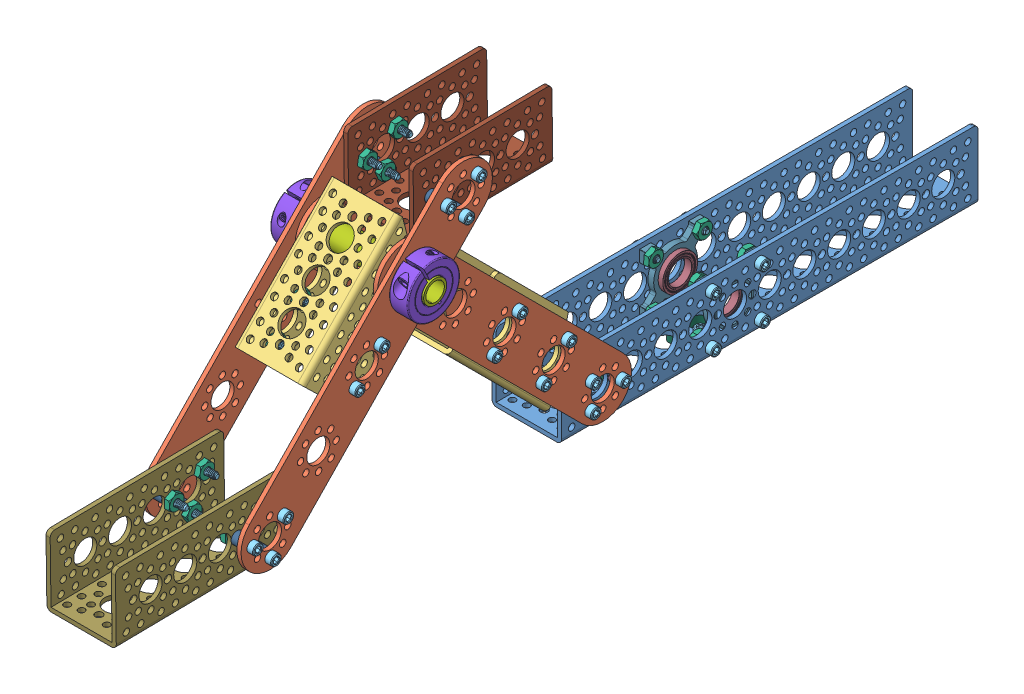
SolidWorks assembly Rocker-Bogie Assembly, configuration Default. Lengths in mm.
Overall size (76.23 183.82 473.44).
136 component instances, 15 part files, 99 mates.
Components (placement in the parent):
- 9 Aluminum Channel-1: 9 Aluminum Channel [Default] at (-19.05 0 0) size (38.1 38.1 228.6)
- Pattern F Bracket-1: Pattern F Bracket [Default] at (-20.32 72.9315 263.4315) x (0 0.707107 0.707107) z (0 -0.707107 0.707107) size (184.15 2.29 31.75)
- 3 Aluminum Channel Mod-1: 3 Aluminum Channel Mod [Default] at (-19.05 19.05 236.4908) x (1 0 0) z (0 0.707107 0.707107) size (38.1 38.1 76.2)
- 6-32 Washer-3: 6-32 Washer [Default] at (-20.32 12.1352 216.4648) x (0 0 -1) z (1 0 0) size (6.35 6.35 1.27)
- 6-32 Washer-6: 6-32 Washer [Default] at (-20.32 66.0167 270.3463) x (0 0 -1) z (1 0 0) size (6.35 6.35 1.27)
- 6-32 Washer-7: 6-32 Washer [Default] at (-20.32 79.8463 256.5167) x (0 0 -1) z (1 0 0) size (6.35 6.35 1.27)
- 6-32 Washer-8: 6-32 Washer [Default] at (-20.32 52.9056 229.576) x (0 -0.924225 -0.381849) z (1 0 0) size (6.35 6.35 1.27)
- 6-32 Washer-9: 6-32 Washer [Default] at (-20.32 39.076 243.4056) x (0 0 -1) z (1 0 0) size (6.35 6.35 1.27)
- 6-32_SHCS-2: 6-32_SHCS [6-32 SHCS X .375] at (-13.081 66.0167 270.3463) x (0 0.924225 0.381849) z (-1 0 0) size (5.74 5.74 13.03)
- 6-32_SHCS-6: 6-32_SHCS [6-32 SHCS X .375] at (-13.081 79.8463 256.5167) x (0 0.924225 0.381849) z (-1 0 0) size (5.74 5.74 13.03)
- 6-32_SHCS-7: 6-32_SHCS [6-32 SHCS X .375] at (-13.081 52.9056 229.576) x (0 0.924225 0.381849) z (-1 0 0) size (5.74 5.74 13.03)
- 6-32_SHCS-8: 6-32_SHCS [6-32 SHCS X .375] at (-13.081 12.1352 216.4648) x (0 0.924225 0.381849) z (-1 0 0) size (5.74 5.74 13.03)
- 6-32_SHCS-9: 6-32_SHCS [6-32 SHCS X .375] at (-13.081 39.076 243.4056) x (0 0 1) z (-1 0 0) size (5.74 5.74 13.03)
- hex_nut-1: hex_nut [#6-32] at (-16.764 79.8463 256.5167) x (0 0.381849 -0.924225) z (0 -0.924225 -0.381849) size (7.92 2.9 10.06)
- hex_nut-2: hex_nut [#6-32] at (-16.764 39.076 243.4056) x (0 0.381849 -0.924225) z (0 -0.924225 -0.381849) size (7.92 2.9 10.06)
- hex_nut-3: hex_nut [#6-32] at (-16.764 12.1352 216.4648) x (0 0.381849 -0.924225) z (0 -0.924225 -0.381849) size (7.92 2.9 10.06)
- hex_nut-4: hex_nut [#6-32] at (-16.764 52.9056 229.576) x (0 -0.870942 -0.491386) z (0 -0.491386 0.870942) size (7.92 2.9 10.06)
- hex_nut-5: hex_nut [#6-32] at (-16.764 66.0167 270.3463) x (0 0.381849 -0.924225) z (0 -0.924225 -0.381849) size (7.92 2.9 10.06)
- hex_nut-10: hex_nut [#6-32] at (-16.764 18.8793 199.7725) x (0 0.399577 0.9167) z (0 0.9167 -0.399577) size (7.92 2.9 10.06)
- hex_nut-11: hex_nut [#6-32] at (-16.764 26.2019 216.2193) x (0 -0.936988 -0.349362) z (0 -0.349362 0.936988) size (7.92 2.9 10.06)
- 6-32 Washer-10: 6-32 Washer [Default] at (-20.32 18.8793 199.7725) x (0 0.71934 0.694658) z (1 0 0) size (6.35 6.35 1.27)
- 6-32 Washer-11: 6-32 Washer [Default] at (-20.32 26.2019 216.2193) x (0 -0.999391 0.034899) z (1 0 0) size (6.35 6.35 1.27)
- 6-32_SHCS-10: 6-32_SHCS [6-32 SHCS X .375] at (-13.081 18.8793 199.7725) x (0 -0.9167 0.399577) z (-1 0 0) size (5.74 5.74 13.03)
- 6-32_SHCS-11: 6-32_SHCS [6-32 SHCS X .375] at (-13.081 26.2019 216.2193) x (0 0.349362 -0.936988) z (-1 0 0) size (5.74 5.74 13.03)
- 3inch Aluminum Rod-1: 3inch Aluminum Rod [Default] at (-37.7507 126.8131 317.3131) x (1 0 0) z (0 0.999969 -0.00781) size (76.2 12.7 12.7)
- .5in Collared Clamp-1: .5in Collared Clamp [6157K14] at (-32.5914 126.8131 317.3131) x (0 -0.43021 0.902729) z (-1 0 0) size (28.57 28.59 10.38)
- 0.5 Nylon Plastic Washer-1: 0.5 Nylon Plastic Washer [Default] at (-25.146 126.8131 317.3131) x (0 0 -1) z (1 0 0) size (19.05 19.05 1.27)
- 0.5 Nylon Plastic Washer-2: 0.5 Nylon Plastic Washer [Default] at (-19.05 126.8131 317.3131) x (0 0 1) z (-1 0 0) size (19.05 19.05 1.27)
- 0.5 Nylon Plastic Washer-3: 0.5 Nylon Plastic Washer [Default] at (-22.606 126.8131 317.3131) x (0 0 1) z (-1 0 0) size (19.05 19.05 1.27)
- Pattern F Bracket-2: Pattern F Bracket [Default] at (-27.432 99.4919 343.868) x (0 -0.717092 0.696979) z (0 0.696979 0.717092) size (184.15 2.29 31.75)
- 3 Aluminum Channel Mod-2: 3 Aluminum Channel Mod [Default] at (19.05 153.7511 317.6962) x (-1 0 0) z (0 -0.717092 0.696979) size (38.1 38.1 76.2)
- 6-32_L0_25 Spacer-1: 6-32_L0_25 Spacer [Default] at (-25.4 92.4794 350.6837) size (6.35 6.35 6.35)
- 6-32_L0_25 Spacer-2: 6-32_L0_25 Spacer [Default] at (-25.4 144.3563 290.6191) size (6.35 6.35 6.35)
- 6-32_L0_25 Spacer-4: 6-32_L0_25 Spacer [Default] at (-25.4 35.0715 396.8387) size (6.35 6.35 6.35)
- 6-32_L0_25 Spacer-5: 6-32_L0_25 Spacer [Default] at (-25.4 106.5043 337.0522) size (6.35 6.35 6.35)
- 3 Aluminum Channel-1: 3 Aluminum Channel [Default] at (-19.05 135.899 233.343) x (1 0 0) z (0 -0.014222 0.999899) size (38.1 38.1 76.2)
- 6-32_SHCS-12: 6-32_SHCS [6-32 SHCS X .750] at (-8.382 92.4794 350.6837) x (0 0.924225 0.381849) z (-1 0 0) size (5.74 5.74 22.56)
- 6-32_SHCS-13: 6-32_SHCS [6-32 SHCS X .750] at (-8.382 144.3563 290.6191) x (0 0.924225 0.381849) z (-1 0 0) size (5.74 5.74 22.56)
- 6-32_SHCS-15: 6-32_SHCS [6-32 SHCS X .750] at (-8.382 106.5043 337.0522) x (0 0.924225 0.381849) z (-1 0 0) size (5.74 5.74 22.56)
- 6-32_SHCS-16: 6-32_SHCS [6-32 SHCS X .750] at (-8.382 35.0715 396.8387) x (0 0 1) z (-1 0 0) size (5.74 5.74 22.56)
- 3.75 Aluminum Channel-1: 3.75 Aluminum Channel [Default] at (-19.05 26.0724 377.6588) x (1 0 0) z (0 -0.014222 0.999899) size (38.1 38.1 95.25)
- hex_nut-12: hex_nut [#6-32] at (-16.764 144.3563 290.6191) x (0 0.381849 -0.924225) z (0 -0.924225 -0.381849) size (7.92 2.9 10.06)
- hex_nut-14: hex_nut [#6-32] at (-16.764 106.5043 337.0522) x (0 0.425863 -0.904788) z (0 -0.904788 -0.425863) size (7.92 2.9 10.06)
- hex_nut-15: hex_nut [#6-32] at (-16.764 92.4794 350.6837) x (0 0.425863 -0.904788) z (0 -0.904788 -0.425863) size (7.92 2.9 10.06)
- hex_nut-16: hex_nut [#6-32] at (-16.764 35.0715 396.8387) x (0 -1 0) z (0 0 1) size (7.92 2.9 10.06)
- hex_nut-17: hex_nut [#6-32] at (-16.764 161.0267 283.8211) x (0 0.399577 0.9167) z (0 0.9167 -0.399577) size (7.92 2.9 10.06)
- hex_nut-18: hex_nut [#6-32] at (-16.764 154.3365 300.5351) x (0 -0.936988 -0.349362) z (0 -0.349362 0.936988) size (7.92 2.9 10.06)
- 6-32_L0_25 Spacer-6: 6-32_L0_25 Spacer [Default] at (-25.4 161.0267 283.8211) x (1 0 0) z (0 -0.71934 -0.694658) size (6.35 6.35 6.35)
- 6-32_L0_25 Spacer-7: 6-32_L0_25 Spacer [Default] at (-25.4 154.3365 300.5351) x (1 0 0) z (0 0.999391 -0.034899) size (6.35 6.35 6.35)
- 6-32_SHCS-17: 6-32_SHCS [6-32 SHCS X .750] at (-8.382 161.0267 283.8211) x (0 -0.9167 0.399577) z (-1 0 0) size (5.74 5.74 22.56)
- 6-32_SHCS-18: 6-32_SHCS [6-32 SHCS X .750] at (-8.382 154.3365 300.5351) x (0 0.349362 -0.936988) z (-1 0 0) size (5.74 5.74 22.56)
- hex_nut-19: hex_nut [#6-32] at (-16.764 51.7419 390.0407) x (0 0.694658 -0.71934) z (0 -0.71934 -0.694658) size (7.92 2.9 10.06)
- hex_nut-20: hex_nut [#6-32] at (-16.764 45.0518 406.7547) x (0 0.034899 0.999391) z (0 0.999391 -0.034899) size (7.92 2.9 10.06)
- 6-32_L0_25 Spacer-8: 6-32_L0_25 Spacer [Default] at (-25.4 51.7419 390.0407) x (1 0 0) z (0 -0.71934 -0.694658) size (6.35 6.35 6.35)
- 6-32_L0_25 Spacer-9: 6-32_L0_25 Spacer [Default] at (-25.4 45.0518 406.7547) x (1 0 0) z (0 0.999391 -0.034899) size (6.35 6.35 6.35)
- 6-32_SHCS-19: 6-32_SHCS [6-32 SHCS X .750] at (-8.382 51.7419 390.0407) x (0 -0.71934 -0.694658) z (-1 0 0) size (5.74 5.74 22.56)
- 6-32_SHCS-20: 6-32_SHCS [6-32 SHCS X .750] at (-8.382 45.0518 406.7547) x (0 0.999391 -0.034899) z (-1 0 0) size (5.74 5.74 22.56)
- 6-32_L0_25 Spacer-10: 6-32_L0_25 Spacer [Default] at (25.4 45.0518 406.7547) x (-1 0 0) z (0 -0.999391 0.034899) size (6.35 6.35 6.35)
- 6-32_SHCS-21: 6-32_SHCS [6-32 SHCS X .750] at (8.382 45.0518 406.7547) x (0 -0.999391 0.034899) z (1 0 0) size (5.74 5.74 22.56)
- 6-32_SHCS-22: 6-32_SHCS [6-32 SHCS X .750] at (8.382 35.0715 396.8387) x (0 0 -1) z (1 0 0) size (5.74 5.74 22.56)
- 6-32_L0_25 Spacer-11: 6-32_L0_25 Spacer [Default] at (25.4 35.0715 396.8387) x (-1 0 0) z (0 0 -1) size (6.35 6.35 6.35)
- 6-32_L0_25 Spacer-12: 6-32_L0_25 Spacer [Default] at (25.4 51.7419 390.0407) x (-1 0 0) z (0 0.71934 0.694658) size (6.35 6.35 6.35)
- 6-32_SHCS-23: 6-32_SHCS [6-32 SHCS X .750] at (8.382 51.7419 390.0407) x (0 0.71934 0.694658) z (1 0 0) size (5.74 5.74 22.56)
- Pattern F Bracket-3: Pattern F Bracket [Default] at (27.432 99.4919 343.868) x (0 0.717092 -0.696979) z (0 0.696979 0.717092) size (184.15 2.29 31.75)
- hex_nut-21: hex_nut [#6-32] at (16.764 35.0715 396.8387) x (0 -1 0) z (0 0 -1) size (7.92 2.9 10.06)
- hex_nut-22: hex_nut [#6-32] at (16.764 45.0518 406.7547) x (0 0.034899 0.999391) z (0 -0.999391 0.034899) size (7.92 2.9 10.06)
- hex_nut-23: hex_nut [#6-32] at (16.764 51.7419 390.0407) x (0 0.694658 -0.71934) z (0 0.71934 0.694658) size (7.92 2.9 10.06)
- hex_nut-24: hex_nut [#6-32] at (16.764 92.4794 350.6837) x (0 0.425863 -0.904788) z (0 0.904788 0.425863) size (7.92 2.9 10.06)
- 6-32_SHCS-24: 6-32_SHCS [6-32 SHCS X .750] at (8.382 92.4794 350.6837) x (0 -0.924225 -0.381849) z (1 0 0) size (5.74 5.74 22.56)
- 6-32_SHCS-25: 6-32_SHCS [6-32 SHCS X .750] at (8.382 106.5043 337.0522) x (0 -0.924225 -0.381849) z (1 0 0) size (5.74 5.74 22.56)
- hex_nut-25: hex_nut [#6-32] at (16.764 106.5043 337.0522) x (0 0.425863 -0.904788) z (0 0.904788 0.425863) size (7.92 2.9 10.06)
- .5in Collared Clamp-2: .5in Collared Clamp [6157K14] at (32.5914 126.8131 317.3131) x (0 0.43021 -0.902729) z (1 0 0) size (28.57 28.59 10.38)
- 0.5 Nylon Plastic Washer-4: 0.5 Nylon Plastic Washer [Default] at (23.876 126.8131 317.3131) x (0 0 -1) z (1 0 0) size (19.05 19.05 1.27)
- 0.5 Nylon Plastic Washer-5: 0.5 Nylon Plastic Washer [Default] at (23.876 126.8131 317.3131) x (0 0 1) z (-1 0 0) size (19.05 19.05 1.27)
- 0.5 Nylon Plastic Washer-6: 0.5 Nylon Plastic Washer [Default] at (20.32 126.8131 317.3131) x (0 0 1) z (-1 0 0) size (19.05 19.05 1.27)
- 6-32_L0_25 Spacer-13: 6-32_L0_25 Spacer [Default] at (25.4 92.4794 350.6837) x (-1 0 0) z (0 0 -1) size (6.35 6.35 6.35)
- 6-32_L0_25 Spacer-14: 6-32_L0_25 Spacer [Default] at (25.4 106.5043 337.0522) x (-1 0 0) z (0 0 -1) size (6.35 6.35 6.35)
- 6-32_L0_25 Spacer-15: 6-32_L0_25 Spacer [Default] at (25.4 154.3365 300.5351) x (-1 0 0) z (0 -0.999391 0.034899) size (6.35 6.35 6.35)
- 6-32_L0_25 Spacer-16: 6-32_L0_25 Spacer [Default] at (25.4 161.0267 283.8211) x (-1 0 0) z (0 0.71934 0.694658) size (6.35 6.35 6.35)
- 6-32_L0_25 Spacer-17: 6-32_L0_25 Spacer [Default] at (25.4 144.3563 290.6191) x (-1 0 0) z (0 0 -1) size (6.35 6.35 6.35)
- 6-32_SHCS-26: 6-32_SHCS [6-32 SHCS X .750] at (8.382 144.3563 290.6191) x (0 -0.924225 -0.381849) z (1 0 0) size (5.74 5.74 22.56)
- 6-32_SHCS-27: 6-32_SHCS [6-32 SHCS X .750] at (8.382 154.3365 300.5351) x (0 -0.349362 0.936988) z (1 0 0) size (5.74 5.74 22.56)
- 6-32_SHCS-28: 6-32_SHCS [6-32 SHCS X .750] at (8.382 161.0267 283.8211) x (0 0.9167 -0.399577) z (1 0 0) size (5.74 5.74 22.56)
- 6-32_SHCS-29: 6-32_SHCS [6-32 SHCS X .375] at (13.081 79.8463 256.5167) x (0 -0.924225 -0.381849) z (1 0 0) size (5.74 5.74 13.03)
- 6-32_SHCS-30: 6-32_SHCS [6-32 SHCS X .375] at (13.081 52.9056 229.576) x (0 -0.924225 -0.381849) z (1 0 0) size (5.74 5.74 13.03)
- 6-32_SHCS-31: 6-32_SHCS [6-32 SHCS X .375] at (13.081 18.8793 199.7725) x (0 0.9167 -0.399577) z (1 0 0) size (5.74 5.74 13.03)
- 6-32_SHCS-32: 6-32_SHCS [6-32 SHCS X .375] at (13.081 26.2019 216.2193) x (0 -0.349362 0.936988) z (1 0 0) size (5.74 5.74 13.03)
- 6-32_SHCS-33: 6-32_SHCS [6-32 SHCS X .375] at (13.081 39.076 243.4056) x (0 0 -1) z (1 0 0) size (5.74 5.74 13.03)
- 6-32_SHCS-34: 6-32_SHCS [6-32 SHCS X .375] at (13.081 66.0167 270.3463) x (0 -0.924225 -0.381849) z (1 0 0) size (5.74 5.74 13.03)
- 6-32_SHCS-35: 6-32_SHCS [6-32 SHCS X .375] at (13.081 12.1352 216.4648) x (0 -0.924225 -0.381849) z (1 0 0) size (5.74 5.74 13.03)
- 6-32 Washer-12: 6-32 Washer [Default] at (19.05 18.8793 199.7725) x (0 0.71934 0.694658) z (1 0 0) size (6.35 6.35 1.27)
- 6-32 Washer-13: 6-32 Washer [Default] at (19.05 12.1352 216.4648) x (0 0 -1) z (1 0 0) size (6.35 6.35 1.27)
- 6-32 Washer-14: 6-32 Washer [Default] at (19.05 26.2019 216.2193) x (0 -0.999391 0.034899) z (1 0 0) size (6.35 6.35 1.27)
- 6-32 Washer-15: 6-32 Washer [Default] at (19.05 39.076 243.4056) x (0 0 -1) z (1 0 0) size (6.35 6.35 1.27)
- 6-32 Washer-16: 6-32 Washer [Default] at (19.05 52.9056 229.576) x (0 -0.924225 -0.381849) z (1 0 0) size (6.35 6.35 1.27)
- 6-32 Washer-17: 6-32 Washer [Default] at (19.05 79.8463 256.5167) x (0 0 -1) z (1 0 0) size (6.35 6.35 1.27)
- 6-32 Washer-18: 6-32 Washer [Default] at (19.05 66.0167 270.3463) x (0 0 -1) z (1 0 0) size (6.35 6.35 1.27)
- Pattern F Bracket-4: Pattern F Bracket [Default] at (22.606 72.9315 263.4315) x (0 -0.707107 -0.707107) z (0 0.707107 -0.707107) size (184.15 2.29 31.75)
- 0.5 Pillow Bearing Block-1: 0.5 Pillow Bearing Block [Default] at (-23.869 27.3261 118.2131) x (0 -0.904025 -0.427479) z (0 -0.427479 0.904025) size (44.3 7.64 44.3)
  - 0.5 Bearing-1: 0.5 Bearing [Default] at (1.0111 10.8528 17.222) size (19.05 3.97 19.05)
  - 0.5 Bearing Block-1: 0.5 Bearing Block [Default] at (1.0111 10.28 17.222) x (-0.904025 0 -0.427479) z (-0.427479 0 0.904025) size (33.27 5.08 33.27)
- 0.5 Pillow Bearing Block-2: 0.5 Pillow Bearing Block [Default] at (23.869 3.9131 141.6261) x (0 -0.427479 -0.904025) z (0 0.904025 -0.427479) size (44.3 7.64 44.3)
  - 0.5 Bearing-1: 0.5 Bearing [Default] at (1.0111 10.8528 17.222) size (19.05 3.97 19.05)
  - 0.5 Bearing Block-1: 0.5 Bearing Block [Default] at (1.0111 10.28 17.222) x (-0.904025 0 -0.427479) z (-0.427479 0 0.904025) size (33.27 5.08 33.27)
- 6-32_SHCS-36: 6-32_SHCS [6-32 SHCS X .375] at (-9.525 32.5204 119.8796) x (0 0.00007 1) z (-1 0 0) size (5.74 5.74 13.03)
- hex_nut-26: hex_nut [#6-32] at (-13.589 32.5204 119.8796) x (0 0.442098 -0.896967) z (0 -0.896967 -0.442098) size (7.92 2.9 10.06)
- 6-32_SHCS-37: 6-32_SHCS [6-32 SHCS X .375] at (-9.525 5.5796 119.8796) x (0 1 -0.00007) z (-1 0 0) size (5.74 5.74 13.03)
- 6-32_SHCS-38: 6-32_SHCS [6-32 SHCS X .375] at (-9.525 5.5796 146.8204) x (0 -0.00007 -1) z (-1 0 0) size (5.74 5.74 13.03)
- 6-32_SHCS-39: 6-32_SHCS [6-32 SHCS X .375] at (-9.525 32.5204 146.8204) x (0 -1 0.00007) z (-1 0 0) size (5.74 5.74 13.03)
- hex_nut-27: hex_nut [#6-32] at (-13.589 5.5796 119.8796) x (0 -0.896967 -0.442098) z (0 -0.442098 0.896967) size (7.92 2.9 10.06)
- hex_nut-28: hex_nut [#6-32] at (-13.589 5.5796 146.8204) x (0 -0.442098 0.896967) z (0 0.896967 0.442098) size (7.92 2.9 10.06)
- hex_nut-29: hex_nut [#6-32] at (-13.589 32.5204 146.8204) x (0 0.896967 0.442098) z (0 0.442098 -0.896967) size (7.92 2.9 10.06)
- 6-32_SHCS-40: 6-32_SHCS [6-32 SHCS X .375] at (9.525 32.5204 119.8796) x (0 -0.00007 -1) z (1 0 0) size (5.74 5.74 13.03)
- hex_nut-30: hex_nut [#6-32] at (13.589 32.5204 119.8796) x (0 0.442098 -0.896967) z (0 0.896967 0.442098) size (7.92 2.9 10.06)
- 6-32_SHCS-41: 6-32_SHCS [6-32 SHCS X .375] at (9.525 5.5796 119.8796) x (0 -1 0.00007) z (1 0 0) size (5.74 5.74 13.03)
- 6-32_SHCS-42: 6-32_SHCS [6-32 SHCS X .375] at (9.525 5.5796 146.8204) x (0 0.00007 1) z (1 0 0) size (5.74 5.74 13.03)
- 6-32_SHCS-43: 6-32_SHCS [6-32 SHCS X .375] at (9.525 32.5204 146.8204) x (0 1 -0.00007) z (1 0 0) size (5.74 5.74 13.03)
- hex_nut-31: hex_nut [#6-32] at (13.589 5.5796 119.8796) x (0 -0.896967 -0.442098) z (0 0.442098 -0.896967) size (7.92 2.9 10.06)
- hex_nut-32: hex_nut [#6-32] at (13.589 5.5796 146.8204) x (0 -0.442098 0.896967) z (0 -0.896967 -0.442098) size (7.92 2.9 10.06)
- hex_nut-33: hex_nut [#6-32] at (13.589 32.5204 146.8204) x (0 0.896967 0.442098) z (0 -0.442098 0.896967) size (7.92 2.9 10.06)
- 0.5 Bore Side Tapped Clamping Hub-1: 0.5 Bore Side Tapped Clamping Hub [Default] at (33.5255 -18.6705 120.2928) size (20.57 7.21 26.29)
  - 545600-1: 545600 [Default] at (-33.5255 9.1455 13.0572) size (20.57 7.21 26.29)
- 6-32_SHCS-44: 6-32_SHCS [6-32 SHCS X .375] at (-6.9148 -7.239 140.2648) x (1 0 0) z (0 1 0) size (5.74 5.74 13.03)
- 6-32_SHCS-45: 6-32_SHCS [6-32 SHCS X .375] at (-6.9148 -7.239 126.4352) x (0 0 1) z (0 1 0) size (5.74 5.74 13.03)
- 6-32_SHCS-46: 6-32_SHCS [6-32 SHCS X .375] at (6.9148 -7.239 126.4352) x (-1 0 0) z (0 1 0) size (5.74 5.74 13.03)
- 6-32_SHCS-47: 6-32_SHCS [6-32 SHCS X .375] at (6.9148 -7.239 140.2648) x (0 0 -1) z (0 1 0) size (5.74 5.74 13.03)
- hex_nut-34: hex_nut [#6-32] at (16.764 52.9056 229.576) x (0 -0.870942 -0.491386) z (0 0.491386 -0.870942) size (7.92 2.9 10.06)
- hex_nut-35: hex_nut [#6-32] at (16.764 39.076 243.4056) x (0 0.381849 -0.924225) z (0 0.924225 0.381849) size (7.92 2.9 10.06)
- hex_nut-36: hex_nut [#6-32] at (16.764 26.2019 216.2193) x (0 -0.936988 -0.349362) z (0 0.349362 -0.936988) size (7.92 2.9 10.06)
- hex_nut-37: hex_nut [#6-32] at (16.764 12.1352 216.4648) x (0 0.381849 -0.924225) z (0 0.924225 0.381849) size (7.92 2.9 10.06)
- hex_nut-38: hex_nut [#6-32] at (16.764 18.8793 199.7725) x (0 0.399577 0.9167) z (0 -0.9167 0.399577) size (7.92 2.9 10.06)
- hex_nut-39: hex_nut [#6-32] at (16.764 79.8463 256.5167) x (0 0.381849 -0.924225) z (0 0.924225 0.381849) size (7.92 2.9 10.06)
- hex_nut-40: hex_nut [#6-32] at (16.764 66.0167 270.3463) x (0 0.381849 -0.924225) z (0 0.924225 0.381849) size (7.92 2.9 10.06)
- hex_nut-41: hex_nut [#6-32] at (16.764 154.3365 300.5351) x (0 -0.936988 -0.349362) z (0 0.349362 -0.936988) size (7.92 2.9 10.06)
- hex_nut-42: hex_nut [#6-32] at (16.764 161.0267 283.8211) x (0 0.399577 0.9167) z (0 -0.9167 0.399577) size (7.92 2.9 10.06)
- hex_nut-43: hex_nut [#6-32] at (16.764 144.3563 290.6191) x (0 0.381849 -0.924225) z (0 0.924225 0.381849) size (7.92 2.9 10.06)
Mates (geometry in assembly coordinates):
- Concentric1: concentric aligned: cylinder of 9 Aluminum Channel-1 through (19.05 12.1352 216.4648) axis (1 0 0) radius 1.778; cylinder of 6-32_SHCS-8 through (-35.306 12.1352 216.4648) axis (1 0 0) radius 2.8702
- Concentric2: concentric anti-aligned: cylinder of 9 Aluminum Channel-1 through (19.05 12.1352 216.4648) axis (1 0 0) radius 1.778; cylinder of 6-32 Washer-3 through (-19.05 12.1352 216.4648) axis (-1 0 0) radius 3.175
- Concentric3: concentric aligned: cylinder of 9 Aluminum Channel-1 through (19.05 12.1352 216.4648) axis (1 0 0) radius 1.778; cylinder of hex_nut-3 through (-16.6879 12.1352 216.4648) axis (1 0 0) radius 1.323
- Concentric4: concentric aligned: cylinder of 3 Aluminum Channel Mod-1 through (19.05 39.076 243.4056) axis (1 0 0) radius 1.778; cylinder of 6-32_SHCS-9 through (-35.306 39.076 243.4056) axis (1 0 0) radius 2.8702
- Concentric5: concentric anti-aligned: cylinder of 3 Aluminum Channel Mod-1 through (19.05 39.076 243.4056) axis (1 0 0) radius 1.778; cylinder of 6-32 Washer-9 through (-19.05 39.076 243.4056) axis (-1 0 0) radius 3.175
- Concentric6: concentric aligned: cylinder of 3 Aluminum Channel Mod-1 through (19.05 39.076 243.4056) axis (1 0 0) radius 1.778; cylinder of hex_nut-2 through (-16.6879 39.076 243.4056) axis (1 0 0) radius 1.323
- Concentric7: concentric aligned: cylinder of 3 Aluminum Channel Mod-1 through (19.05 52.9056 229.576) axis (1 0 0) radius 1.778; cylinder of 6-32_SHCS-7 through (-35.306 52.9056 229.576) axis (1 0 0) radius 2.8702
- Concentric8: concentric anti-aligned: circle of hex_nut-4; cylinder of 6-32 Washer-8 through (-19.05 52.9056 229.576) axis (-1 0 0) radius 3.175
- Concentric9: concentric aligned: circle of hex_nut-4; cylinder of 3 Aluminum Channel Mod-1 through (19.05 52.9056 229.576) axis (1 0 0) radius 1.778
- Concentric10: concentric anti-aligned: cylinder of 3 Aluminum Channel Mod-1 through (19.05 79.8463 256.5167) axis (1 0 0) radius 1.778; cylinder of 6-32 Washer-7 through (-19.05 79.8463 256.5167) axis (-1 0 0) radius 3.175
- Concentric11: concentric aligned: cylinder of 3 Aluminum Channel Mod-1 through (19.05 79.8463 256.5167) axis (1 0 0) radius 1.778; cylinder of 6-32_SHCS-6 through (-35.306 79.8463 256.5167) axis (1 0 0) radius 2.8702
- Concentric12: concentric aligned: cylinder of 3 Aluminum Channel Mod-1 through (19.05 79.8463 256.5167) axis (1 0 0) radius 1.778; cylinder of hex_nut-1 through (-16.6879 79.8463 256.5167) axis (1 0 0) radius 1.323
- Concentric13: concentric anti-aligned: cylinder of 3 Aluminum Channel Mod-1 through (19.05 66.0167 270.3463) axis (1 0 0) radius 1.778; cylinder of 6-32 Washer-6 through (-19.05 66.0167 270.3463) axis (-1 0 0) radius 3.175
- Concentric14: concentric aligned: cylinder of 3 Aluminum Channel Mod-1 through (19.05 66.0167 270.3463) axis (1 0 0) radius 1.778; cylinder of 6-32_SHCS-2 through (-35.306 66.0167 270.3463) axis (1 0 0) radius 2.8702
- Concentric15: concentric aligned: cylinder of 3 Aluminum Channel Mod-1 through (19.05 66.0167 270.3463) axis (1 0 0) radius 1.778; cylinder of hex_nut-5 through (-16.6879 66.0167 270.3463) axis (1 0 0) radius 1.323
- Coincident1: coincident aligned: plane of 9 Aluminum Channel-1 through (-19.05 0 228.6) normal (-1 0 0); plane of 3 Aluminum Channel Mod-1 through (-19.05 72.9315 290.3723) normal (-1 0 0)
- Coincident2: coincident anti-aligned: plane of 9 Aluminum Channel-1 through (-19.05 0 228.6) normal (-1 0 0); plane of 6-32 Washer-3 through (-19.05 12.1352 216.4648) normal (1 0 0)
- Coincident3: coincident anti-aligned: plane of 9 Aluminum Channel-1 through (-19.05 0 228.6) normal (-1 0 0); plane of 6-32 Washer-9 through (-19.05 39.076 243.4056) normal (1 0 0)
- Coincident5: coincident anti-aligned: plane of 9 Aluminum Channel-1 through (-19.05 0 228.6) normal (-1 0 0); plane of 6-32 Washer-7 through (-19.05 79.8463 256.5167) normal (1 0 0)
- Coincident6: coincident anti-aligned: plane of 9 Aluminum Channel-1 through (-19.05 0 228.6) normal (-1 0 0); plane of 6-32 Washer-6 through (-19.05 66.0167 270.3463) normal (1 0 0)
- Coincident7: coincident anti-aligned: plane of 9 Aluminum Channel-1 through (-19.05 0 228.6) normal (-1 0 0); plane of 6-32 Washer-8 through (-19.05 52.9056 229.576) normal (1 0 0)
- Coincident8: coincident anti-aligned: plane of Pattern F Bracket-1 through (-20.32 19.05 209.55) normal (1 0 0); plane of 6-32 Washer-3 through (-20.32 12.1352 216.4648) normal (-1 0 0)
- Concentric16: concentric anti-aligned: cylinder of 9 Aluminum Channel-1 through (19.05 19.05 209.55) axis (1 0 0) radius 6.3627; cylinder of Pattern F Bracket-1 through (-22.606 19.05 209.55) axis (-1 0 0) radius 6.3627
- Concentric17: concentric anti-aligned: cylinder of 9 Aluminum Channel-1 through (19.05 12.1352 216.4648) axis (1 0 0) radius 1.778; cylinder of Pattern F Bracket-1 through (-22.606 12.1352 216.4648) axis (-1 0 0) radius 1.778
- Coincident9: coincident anti-aligned: plane of Pattern F Bracket-1 through (-22.606 19.05 209.55) normal (-1 0 0); plane of 6-32_SHCS-8 through (-22.606 12.1352 216.4648) normal (1 0 0)
- Coincident10: coincident anti-aligned: plane of Pattern F Bracket-1 through (-22.606 19.05 209.55) normal (-1 0 0); plane of 6-32_SHCS-7 through (-22.606 52.9056 229.576) normal (1 0 0)
- Coincident11: coincident anti-aligned: plane of Pattern F Bracket-1 through (-22.606 19.05 209.55) normal (-1 0 0); plane of 6-32_SHCS-9 through (-22.606 39.076 243.4056) normal (1 0 0)
- Coincident12: coincident anti-aligned: plane of Pattern F Bracket-1 through (-22.606 19.05 209.55) normal (-1 0 0); plane of 6-32_SHCS-6 through (-22.606 79.8463 256.5167) normal (1 0 0)
- Coincident13: coincident anti-aligned: plane of Pattern F Bracket-1 through (-22.606 19.05 209.55) normal (-1 0 0); plane of 6-32_SHCS-2 through (-22.606 66.0167 270.3463) normal (1 0 0)
- Concentric18: concentric anti-aligned: cylinder of Pattern F Bracket-1 through (-22.606 45.9908 236.4908) axis (-1 0 0) radius 6.3627; cylinder of 3 Aluminum Channel Mod-1 through (19.05 45.9908 236.4908) axis (1 0 0) radius 6.3627
- Concentric19: concentric anti-aligned: cylinder of Pattern F Bracket-1 through (-22.606 72.9315 263.4315) axis (-1 0 0) radius 6.3627; cylinder of 3 Aluminum Channel Mod-1 through (19.05 72.9315 263.4315) axis (1 0 0) radius 6.3627
- Coincident14: coincident anti-aligned: plane of 9 Aluminum Channel-1 through (-16.764 38.1 228.6) normal (1 0 0); plane of hex_nut-3 through (-16.764 16.9652 222.7476) normal (-1 0 0)
- Coincident15: coincident anti-aligned: plane of 9 Aluminum Channel-1 through (-16.764 38.1 228.6) normal (1 0 0); plane of hex_nut-2 through (-16.764 43.906 249.6884) normal (-1 0 0)
- Coincident16: coincident anti-aligned: plane of 9 Aluminum Channel-1 through (-16.764 38.1 228.6) normal (1 0 0); plane of hex_nut-4 through (-16.764 59.729 225.5457) normal (-1 0 0)
- Coincident17: coincident anti-aligned: plane of 9 Aluminum Channel-1 through (-16.764 38.1 228.6) normal (1 0 0); plane of hex_nut-5 through (-16.764 70.8467 276.6291) normal (-1 0 0)
- Coincident18: coincident anti-aligned: plane of 9 Aluminum Channel-1 through (-16.764 38.1 228.6) normal (1 0 0); plane of hex_nut-1 through (-16.764 84.6763 262.7995) normal (-1 0 0)
- Concentric20: concentric anti-aligned: cylinder of Pattern F Bracket-1 through (-22.606 126.8131 317.3131) axis (-1 0 0) radius 6.3627; circle of 0.5 Nylon Plastic Washer-1
- Concentric21: concentric anti-aligned: cylinder of Pattern F Bracket-1 through (-22.606 126.8131 317.3131) axis (-1 0 0) radius 6.3627; cylinder of 0.5 Nylon Plastic Washer-3 through (-23.876 126.8131 317.3131) axis (1 0 0) radius 6.35
- Concentric22: concentric anti-aligned: cylinder of Pattern F Bracket-1 through (-22.606 126.8131 317.3131) axis (-1 0 0) radius 6.3627; cylinder of 0.5 Nylon Plastic Washer-2 through (-20.32 126.8131 317.3131) axis (1 0 0) radius 6.35
- Concentric23: concentric aligned: cylinder of Pattern F Bracket-1 through (-22.606 126.8131 317.3131) axis (-1 0 0) radius 6.3627; cylinder of 3inch Aluminum Rod-1 through (38.4492 126.8131 317.3131) axis (-1 0 0) radius 6.35
- Concentric24: concentric anti-aligned: cylinder of Pattern F Bracket-1 through (-22.606 126.8131 317.3131) axis (-1 0 0) radius 6.3627; cylinder of .5in Collared Clamp-1 through (-37.7507 126.8131 317.3131) axis (1 0 0) radius 6.35
- Concentric25: concentric anti-aligned: cylinder of Pattern F Bracket-1 through (-22.606 126.8131 317.3131) axis (-1 0 0) radius 6.3627; cylinder of Pattern F Bracket-2 through (-25.146 126.8131 317.3131) axis (1 0 0) radius 6.3627
- Concentric26: concentric aligned: cylinder of 3inch Aluminum Rod-1 through (38.4492 126.8131 317.3131) axis (-1 0 0) radius 6.35; cylinder of 3 Aluminum Channel Mod-2 through (-19.05 126.8131 317.3131) axis (-1 0 0) radius 6.3627
- Coincident19: coincident anti-aligned: plane of 0.5 Nylon Plastic Washer-2 through (-19.05 126.8131 317.3131) normal (1 0 0); plane of 3 Aluminum Channel Mod-2 through (-19.05 72.5538 343.4848) normal (-1 0 0)
- Coincident20: coincident anti-aligned: plane of Pattern F Bracket-1 through (-20.32 19.05 209.55) normal (1 0 0); plane of 0.5 Nylon Plastic Washer-2 through (-20.32 126.8131 317.3131) normal (-1 0 0)
- Coincident21: coincident anti-aligned: plane of 0.5 Nylon Plastic Washer-1 through (-23.876 126.8131 317.3131) normal (1 0 0); plane of 0.5 Nylon Plastic Washer-3 through (-23.876 126.8131 317.3131) normal (-1 0 0)
- Coincident22: coincident anti-aligned: plane of Pattern F Bracket-1 through (-22.606 19.05 209.55) normal (-1 0 0); plane of 0.5 Nylon Plastic Washer-3 through (-22.606 126.8131 317.3131) normal (1 0 0)
- Coincident23: coincident anti-aligned: plane of 0.5 Nylon Plastic Washer-1 through (-25.146 126.8131 317.3131) normal (-1 0 0); plane of Pattern F Bracket-2 through (-25.146 154.1343 290.7582) normal (1 0 0)
- Coincident24: coincident anti-aligned: plane of .5in Collared Clamp-1 through (-27.432 126.8131 317.3131) normal (1 0 0); plane of Pattern F Bracket-2 through (-27.432 154.1343 290.7582) normal (-1 0 0)
- Concentric31: concentric anti-aligned: cylinder of Pattern F Bracket-2 through (-25.146 92.6761 336.8555) axis (1 0 0) radius 1.778; cylinder of 3 Aluminum Channel Mod-2 through (-19.05 92.6761 336.8555) axis (-1 0 0) radius 1.778
- Concentric32: concentric aligned: cylinder of 6-32_L0_25 Spacer-5 through (-25.4 106.5043 337.0522) axis (1 0 0) radius 1.651; cylinder of Pattern F Bracket-2 through (-25.146 106.5043 337.0522) axis (1 0 0) radius 1.778
- Concentric33: concentric aligned: cylinder of 6-32_L0_25 Spacer-5 through (-25.4 106.5043 337.0522) axis (1 0 0) radius 1.651; cylinder of hex_nut-14 through (-16.6879 106.5043 337.0522) axis (1 0 0) radius 1.323
- Concentric34: concentric aligned: cylinder of 6-32_L0_25 Spacer-5 through (-25.4 106.5043 337.0522) axis (1 0 0) radius 1.651; cylinder of 6-32_SHCS-15 through (-40.132 106.5043 337.0522) axis (1 0 0) radius 2.8702
- Concentric35: concentric anti-aligned: cylinder of Pattern F Bracket-2 through (-25.146 92.4794 350.6837) axis (1 0 0) radius 1.778; cylinder of 6-32_L0_25 Spacer-1 through (-19.05 92.4794 350.6837) axis (-1 0 0) radius 3.175
- Concentric36: concentric aligned: cylinder of Pattern F Bracket-2 through (-25.146 92.4794 350.6837) axis (1 0 0) radius 1.778; cylinder of hex_nut-15 through (-16.6879 92.4794 350.6837) axis (1 0 0) radius 1.323
- Concentric37: concentric aligned: cylinder of Pattern F Bracket-2 through (-25.146 92.4794 350.6837) axis (1 0 0) radius 1.778; cylinder of 6-32_SHCS-12 through (-40.132 92.4794 350.6837) axis (1 0 0) radius 2.8702
- Concentric38: concentric aligned: cylinder of Pattern F Bracket-2 through (-25.146 44.8495 396.9778) axis (1 0 0) radius 6.3627; cylinder of 3.75 Aluminum Channel-1 through (19.05 44.8495 396.9778) axis (1 0 0) radius 6.3627
- Concentric39: concentric aligned: cylinder of Pattern F Bracket-2 through (-25.146 35.0715 396.8387) axis (1 0 0) radius 1.778; cylinder of 3.75 Aluminum Channel-1 through (19.05 35.0715 396.8387) axis (1 0 0) radius 1.778
- Concentric40: concentric anti-aligned: cylinder of 6-32_L0_25 Spacer-4 through (-19.05 35.0715 396.8387) axis (-1 0 0) radius 3.175; cylinder of Pattern F Bracket-2 through (-25.146 35.0715 396.8387) axis (1 0 0) radius 1.778
- Concentric41: concentric anti-aligned: cylinder of 6-32_L0_25 Spacer-4 through (-19.05 35.0715 396.8387) axis (-1 0 0) radius 3.175; cylinder of 6-32_SHCS-16 through (-40.132 35.0715 396.8387) axis (1 0 0) radius 2.8702
- Concentric42: concentric anti-aligned: cylinder of 6-32_L0_25 Spacer-4 through (-19.05 35.0715 396.8387) axis (-1 0 0) radius 3.175; cylinder of hex_nut-16 through (-16.6879 35.0715 396.8387) axis (1 0 0) radius 1.323
- Coincident28: coincident aligned: plane of 3.75 Aluminum Channel-1 through (-19.05 24.7177 472.8991) normal (-1 0 0); plane of 9 Aluminum Channel-1 through (-19.05 0 228.6) normal (-1 0 0)
- Coincident29: coincident aligned: plane of 3.75 Aluminum Channel-1 through (-19.05 24.7177 472.8991) normal (-1 0 0); plane of 3 Aluminum Channel-1 through (-19.05 134.8153 309.5353) normal (-1 0 0)
- Concentric43: concentric aligned: cylinder of Pattern F Bracket-2 through (-25.146 154.1343 290.7582) axis (1 0 0) radius 6.3627; cylinder of 3 Aluminum Channel-1 through (19.05 154.1343 290.7582) axis (1 0 0) radius 6.3627
- Concentric44: concentric aligned: cylinder of Pattern F Bracket-2 through (-25.146 144.3563 290.6191) axis (1 0 0) radius 1.778; cylinder of 3 Aluminum Channel-1 through (19.05 144.3563 290.6191) axis (1 0 0) radius 1.778
- Concentric45: concentric anti-aligned: cylinder of Pattern F Bracket-2 through (-25.146 144.3563 290.6191) axis (1 0 0) radius 1.778; cylinder of 6-32_L0_25 Spacer-2 through (-19.05 144.3563 290.6191) axis (-1 0 0) radius 3.175
- Concentric46: concentric aligned: cylinder of Pattern F Bracket-2 through (-25.146 144.3563 290.6191) axis (1 0 0) radius 1.778; cylinder of 6-32_SHCS-13 through (-40.132 144.3563 290.6191) axis (1 0 0) radius 2.8702
- Concentric47: concentric aligned: cylinder of Pattern F Bracket-2 through (-25.146 144.3563 290.6191) axis (1 0 0) radius 1.778; cylinder of hex_nut-12 through (-16.6879 144.3563 290.6191) axis (1 0 0) radius 1.323
- Coincident30: coincident anti-aligned: plane of Pattern F Bracket-2 through (-27.432 154.1343 290.7582) normal (-1 0 0); plane of 6-32_SHCS-12 through (-27.432 92.4794 350.6837) normal (1 0 0)
- Coincident31: coincident anti-aligned: plane of Pattern F Bracket-2 through (-27.432 154.1343 290.7582) normal (-1 0 0); plane of 6-32_SHCS-15 through (-27.432 106.5043 337.0522) normal (1 0 0)
- Coincident32: coincident anti-aligned: plane of Pattern F Bracket-2 through (-27.432 154.1343 290.7582) normal (-1 0 0); plane of 6-32_SHCS-13 through (-27.432 144.3563 290.6191) normal (1 0 0)
- Coincident33: coincident anti-aligned: plane of Pattern F Bracket-2 through (-27.432 154.1343 290.7582) normal (-1 0 0); plane of 6-32_SHCS-16 through (-27.432 35.0715 396.8387) normal (1 0 0)
- Coincident34: coincident anti-aligned: plane of 3.75 Aluminum Channel-1 through (-16.764 62.8139 473.441) normal (1 0 0); plane of hex_nut-16 through (-16.764 39.0339 389.9756) normal (-1 0 0)
- Coincident35: coincident anti-aligned: plane of 3.75 Aluminum Channel-1 through (-16.764 62.8139 473.441) normal (1 0 0); plane of hex_nut-15 through (-16.764 97.0016 357.1916) normal (-1 0 0)
- Coincident36: coincident anti-aligned: plane of 3.75 Aluminum Channel-1 through (-16.764 62.8139 473.441) normal (1 0 0); plane of hex_nut-14 through (-16.764 111.0265 343.5601) normal (-1 0 0)
- Coincident37: coincident anti-aligned: plane of 3.75 Aluminum Channel-1 through (-16.764 62.8139 473.441) normal (1 0 0); plane of hex_nut-12 through (-16.764 149.1862 296.9019) normal (-1 0 0)
- Concentric48: concentric anti-aligned: cylinder of 0.5 Pillow Bearing Block-1/0.5 Bearing-1 through (-11.0319 19.05 133.35) axis (-1 0 0) radius 6.35; cylinder of 0.5 Pillow Bearing Block-2/0.5 Bearing-1 through (11.0319 19.05 133.35) axis (1 0 0) radius 6.35
- Concentric49: concentric anti-aligned: cylinder of 0.5 Pillow Bearing Block-1/0.5 Bearing-1 through (-11.0319 19.05 133.35) axis (-1 0 0) radius 6.35; cylinder of 9 Aluminum Channel-1 through (19.05 19.05 133.35) axis (1 0 0) radius 6.3627
- Concentric50: concentric aligned: cylinder of 6-32_SHCS-36 through (-31.75 32.5204 119.8796) axis (1 0 0) radius 2.8702; cylinder of 9 Aluminum Channel-1 through (19.05 32.5204 119.8796) axis (1 0 0) radius 1.778
- Concentric51: concentric aligned: cylinder of 6-32_SHCS-36 through (-31.75 32.5204 119.8796) axis (1 0 0) radius 2.8702; cylinder of hex_nut-26 through (-11.9254 32.5204 119.8796) axis (1 0 0) radius 1.323
- Coincident46: coincident aligned: plane of 9 Aluminum Channel-1 through (-19.05 0 228.6) normal (-1 0 0); circle of 6-32_SHCS-36
- Concentric53: concentric aligned: cylinder of 9 Aluminum Channel-1 through (0 0 133.35) axis (0 -1 0) radius 6.3627; cylinder of 0.5 Bore Side Tapped Clamping Hub-1/545600-1 through (0 -9.525 133.35) axis (0 -1 0) radius 6.35
- Concentric54: concentric aligned: cylinder of 6-32_SHCS-44 through (-6.9148 14.986 140.2648) axis (0 -1 0) radius 2.8702; cylinder of 9 Aluminum Channel-1 through (-6.9148 0 140.2648) axis (0 -1 0) radius 1.778
- Concentric55: concentric aligned: cylinder of 6-32_SHCS-44 through (-6.9148 14.986 140.2648) axis (0 -1 0) radius 2.8702; cylinder of 0.5 Bore Side Tapped Clamping Hub-1/545600-1 through (-6.9148 1.9119 140.2648) axis (0 -1 0) radius 1.7526
- Coincident47: coincident anti-aligned: plane of 9 Aluminum Channel-1 through (19.05 0 228.6) normal (0 -1 0); plane of 0.5 Bore Side Tapped Clamping Hub-1/545600-1 through (0 0 133.35) normal (0 1 0)
- Coincident48: coincident anti-aligned: plane of 9 Aluminum Channel-1 through (-16.764 2.286 228.6) normal (0 1 0); plane of 6-32_SHCS-44 through (-6.9148 2.286 140.2648) normal (0 -1 0)
- Concentric56: concentric anti-aligned: cylinder of 0.5 Pillow Bearing Block-2/0.5 Bearing Block-1 through (16.764 32.5204 146.8204) axis (1 0 0) radius 1.778; cylinder of 6-32_SHCS-43 through (31.75 32.5204 146.8204) axis (-1 0 0) radius 2.8702
- Concentric57: concentric anti-aligned: cylinder of 0.5 Pillow Bearing Block-1/0.5 Bearing Block-1 through (-16.764 32.5204 146.8204) axis (-1 0 0) radius 1.778; cylinder of 6-32_SHCS-39 through (-31.75 32.5204 146.8204) axis (1 0 0) radius 2.8702
- Coincident49: coincident aligned: plane of 3inch Aluminum Rod-1 through (-37.7507 126.8131 317.3131) normal (-1 0 0); plane of .5in Collared Clamp-1 through (-37.7507 126.8131 317.3131) normal (-1 0 0)
- Coincident50: coincident anti-aligned: plane of 9 Aluminum Channel-1 through (-16.764 38.1 228.6) normal (1 0 0); plane of 0.5 Pillow Bearing Block-1/0.5 Bearing Block-1 through (-16.764 19.05 133.35) normal (-1 0 0)
- Coincident51: coincident anti-aligned: plane of 9 Aluminum Channel-1 through (16.764 2.286 228.6) normal (-1 0 0); plane of 0.5 Pillow Bearing Block-2/0.5 Bearing Block-1 through (16.764 19.05 133.35) normal (1 0 0)
- Coincident52: coincident anti-aligned: plane of 0.5 Pillow Bearing Block-1/0.5 Bearing Block-1 through (-13.589 19.05 133.35) normal (1 0 0); plane of hex_nut-29 through (-13.589 25.9321 151.2246) normal (-1 0 0)
- Coincident53: coincident anti-aligned: circle of 6-32_L0_25 Spacer-4; plane of 3.75 Aluminum Channel-1 through (-19.05 24.7177 472.8991) normal (-1 0 0)
- Coincident54: coincident anti-aligned: circle of 6-32_L0_25 Spacer-1; plane of 3.75 Aluminum Channel-1 through (-19.05 24.7177 472.8991) normal (-1 0 0)
- Coincident55: coincident anti-aligned: plane of 3 Aluminum Channel Mod-2 through (-19.05 72.5538 343.4848) normal (-1 0 0); circle of 6-32_L0_25 Spacer-2
- Coincident56: coincident anti-aligned: plane of 3 Aluminum Channel Mod-2 through (-19.05 72.5538 343.4848) normal (-1 0 0); circle of 6-32_L0_25 Spacer-5
- Coincident57: coincident: point of 9 Aluminum Channel-1
- Coincident58: coincident anti-aligned: plane of 9 Aluminum Channel-1 through (-19.05 0 0) normal (0 0 -1)
- Coincident59: coincident anti-aligned: plane of 9 Aluminum Channel-1 through (19.05 0 228.6) normal (0 -1 0)
